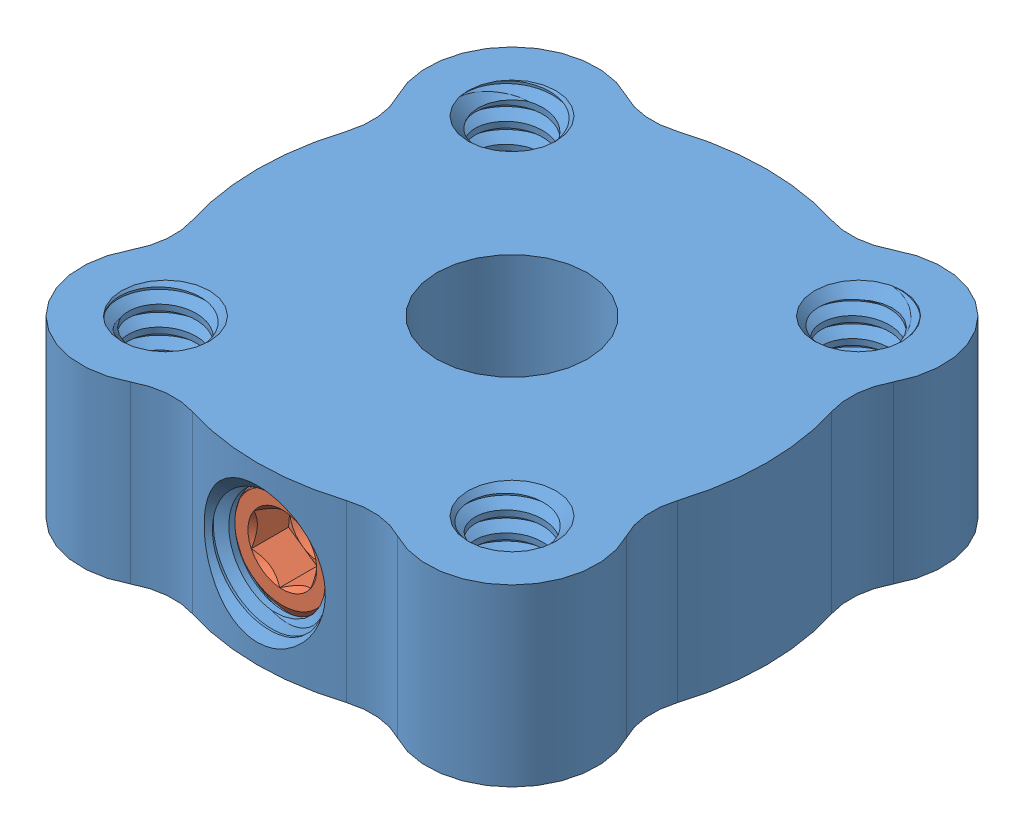
SolidWorks assembly 545576_assembly, configuration Default. Lengths in mm.
Overall size (20.57 9.63 20.57).
2 component instances, 2 part files, 1 mates.
Components (placement in the parent):
- 545576-1: 545576 [Default] at (-12.9847 18.2935 -8.8471) size (20.57 9.63 20.57)
- 545576_10-32_set_screw-3: 545576_10-32_set_screw [Default] at (-12.9847 24.326 -2.4599) x (0.43053 -0.902576 0) z (0 0 1) size (4.98 4.83 6.49)
Mates (geometry in assembly coordinates):
- Screw5: screw = 32 anti-aligned: cylinder of 545576-1 through (-12.9847 24.326 9.9619) axis (0 0 -1) radius 2.413; cylinder of 545576_10-32_set_screw-3 through (-12.9847 24.326 -5.2376) axis (0 0 1) radius 2.413
